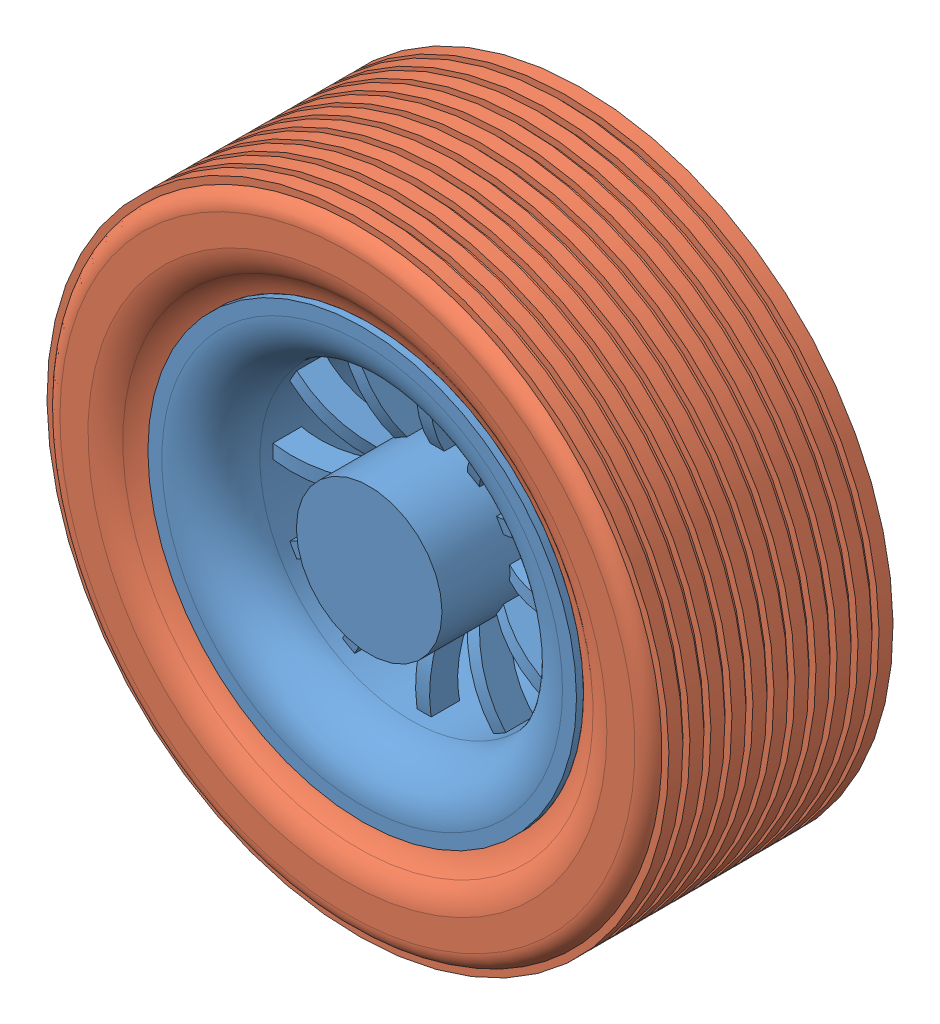
SolidWorks assembly Rueda3, configuration Predeterminado. Lengths in mm.
Overall size (56.94 56.94 17.5).
2 component instances, 2 part files, 2 mates.
Components (placement in the parent):
- Rin3-1: Rin3 [Predeterminado] at (4.323 10.5575 -12.05) size (30.6 30.6 15.39)
- Rueda3-1: Rueda3 [Predeterminado] at (4.323 10.5575 -1.3462) x (0 0 -1) z (0.939286 -0.343135 0) size (17.5 44.4 44.4)
Mates (geometry in assembly coordinates):
- Concéntrica1: concentric anti-aligned: circle of Rin3-1; circle of Rueda3-1
- Coincidente1: coincident anti-aligned: plane of Rin3-1 through (4.323 25.8575 -8.54) normal (0 0 1); plane of Rueda3-1 through (9.5726 24.9276 -8.54) normal (0 0 -1)
